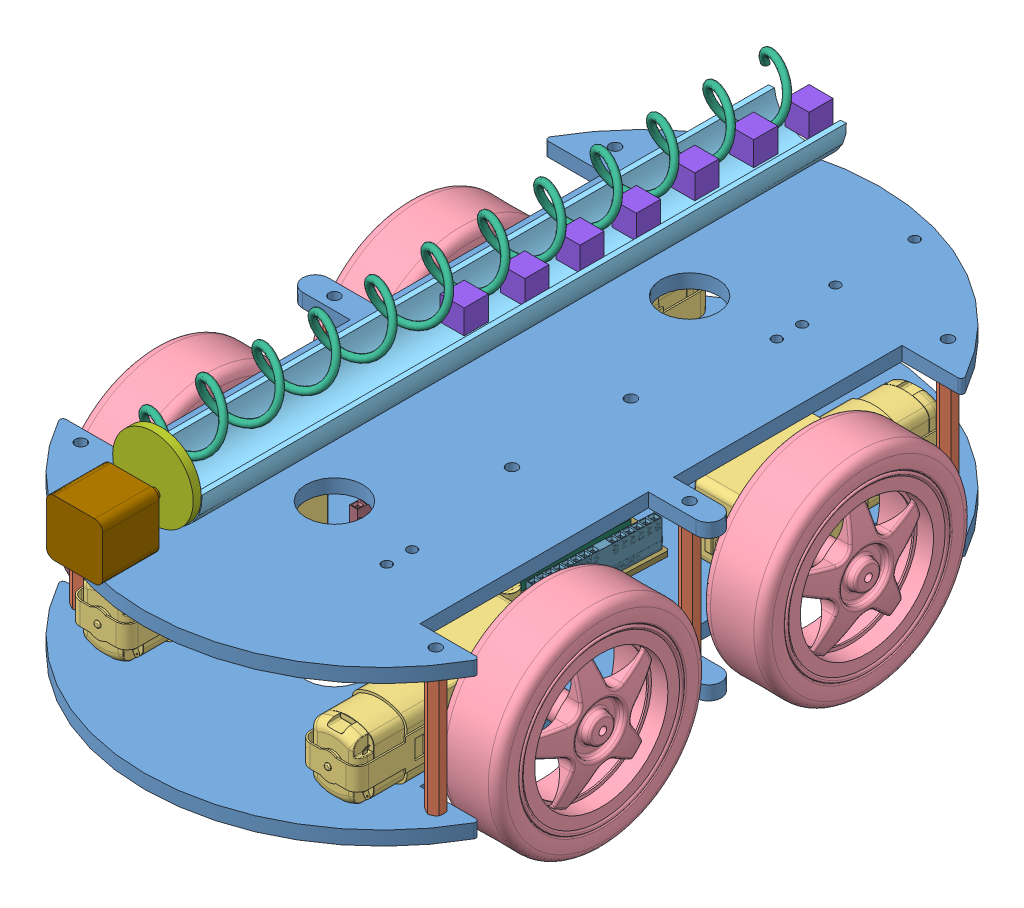
SolidWorks assembly mechatronics project assembly, configuration Default. Lengths in mm.
Overall size (144 110.42 232.39).
47 component instances, 28 part files, 49 mates.
Components (placement in the parent):
- Base Plate-1: Base Plate [Default] at origin size (132 4.4 231.81)
- Long Hex Nut-1: Long Hex Nut [B18.2.4.1M - Hex nut, Style 1,  M3 x 0.5 --D-N] at (-56 44.4 80) x (-0.471141 0 -0.882058) z (0 1 0) size (4.5 5.2 40)
- Long Hex Nut-5: Long Hex Nut [B18.2.4.1M - Hex nut, Style 1,  M3 x 0.5 --D-N] at (56 44.4 0) x (1 0 0) z (0 1 0) size (4.5 5.2 40)
- Long Hex Nut-6: Long Hex Nut [B18.2.4.1M - Hex nut, Style 1,  M3 x 0.5 --D-N] at (56 44.4 80) x (1 0 0) z (0 1 0) size (4.5 5.2 40)
- Long Hex Nut-7: Long Hex Nut [B18.2.4.1M - Hex nut, Style 1,  M3 x 0.5 --D-N] at (52.5 44.4 -85) x (1 0 0) z (0 1 0) size (4.5 5.2 40)
- Long Hex Nut-8: Long Hex Nut [B18.2.4.1M - Hex nut, Style 1,  M3 x 0.5 --D-N] at (-52.5 44.4 -85) x (1 0 0) z (0 1 0) size (4.5 5.2 40)
- Long Hex Nut-9: Long Hex Nut [B18.2.4.1M - Hex nut, Style 1,  M3 x 0.5 --D-N] at (-56 44.4 0) x (1 0 0) z (0 1 0) size (4.5 5.2 40)
- Base Plate-2: Base Plate [Default] at (0 44.4 0) size (132 4.4 231.81)
- Motor-1: Motor [Predeterminado] at (37.6 15.65 -77.2352) x (0 0 1) z (-1 0 0) size (69.7 22.5 36.8)
- Motor-2: Motor [Predeterminado] at (37.6 15.65 80.1311) x (0 0 -1) z (1 0 0) size (69.7 22.5 36.8)
- Motor-3: Motor [Predeterminado] at (-37.6 15.65 77.5479) x (0 0 -1) z (1 0 0) size (69.7 22.5 36.8)
- Motor-4: Motor [Predeterminado] at (-37.6 15.65 -76) x (0 0 1) z (-1 0 0) size (69.7 22.5 36.8)
- Wheel-1: Wheel [Predeterminado] at (-52 15.65 -39.2) x (-1 0 0) z (0 -0.685524 -0.72805) size (25 66 66)
- Wheel-2: Wheel [Predeterminado] at (52 15.65 -40.4352) x (1 0 0) z (0 0.941369 0.337378) size (25 66 66)
- Wheel-3: Wheel [Predeterminado] at (-52 15.65 40.7479) x (-1 0 0) z (0 -0.719414 -0.694582) size (25 66 66)
- Wheel-4: Wheel [Predeterminado] at (52 15.65 43.3311) x (1 0 0) z (0 -0.162012 0.986789) size (25 66 66)
- Part1-1: Part1 [Default] at (-21.5476 61.119 -114.7007) x (0.997351 0.072745 0) z (0 0 1) size (24.64 12.32 203.2)
- helical spring-1: helical spring [Default] at (-26.075 66.7384 -113.6168) size (19.58 19.58 205.37)
- disc-1: disc [Default] at (-22.1907 61.5 88.4993) x (0.653816 -0.756654 0) z (0 0 1) size (25.4 25.4 2.54)
- cube-1: cube [Default] at (-18.7394 62.6066 -98.7614) x (0.999993 0.003627 0) z (0 0.000021 1) size (7.62 7.62 7.62)
- cube-2: cube [Default] at (-19.6517 61.947 -81.1116) size (7.62 7.62 7.62)
- cube-3: cube [Default] at (-19.7614 60.024 -62.7963) size (7.62 7.62 7.62)
- cube-4: cube [Default] at (-19.8698 60.0971 -45.1118) size (7.62 7.62 7.62)
- cube-5: cube [Default] at (-20.004 59.5149 -27.8581) size (7.62 7.62 7.62)
- cube-6: cube [Default] at (-20.4205 60.6551 -9.1402) size (7.62 7.62 7.62)
- cube-7: cube [Default] at (-18.4626 61.6622 -115.9546) size (7.62 7.62 7.62)
- stepper motor-1: stepper motor [Default] at (-21.5488 57.69 98.6593) size (17.78 17.78 25.4)
- Ardi_UNO.STEP-1: Ardi_UNO.STEP [Default] at (-32.6159 2.8 38.091) x (0.039139 0 -0.999234) z (0 1 0) size (76.36 53.4 14.04)
  - Pins_3fach_q_001.STEP-1: Pins_3fach_q_001.STEP [Default] at (64.19 -23.29 3.21) size (5.08 7.62 11.94)
  - Pins_3fach_q_002.STEP-1: Pins_3fach_q_002.STEP [Default] at (15.78 -9.32 3.21) x (0 1 0) z (0 0 1) size (5.08 7.62 11.94)
  - Ardi_UNO_Platine_001.STEP-1: Ardi_UNO_Platine_001.STEP [Default] at origin size (69 53.4 1.61)
  - Headers_digital_001.STEP-1: Headers_digital_001.STEP [Default] at origin size (47.8 2.55 10.95)
  - Headers_Analog_001.STEP-1: Headers_Analog_001.STEP [Default] at origin size (38.85 2.55 10.95)
  - atmega328_socket_001.STEP-1: atmega328_socket_001.STEP [Default] at origin size (35.5 10 6.2)
  - atmega328_001.STEP-1: atmega328_001.STEP [Default] at origin size (35.36 8.18 5.99)
  - resetButton UNO_001.STEP-1: resetButton UNO_001.STEP [Default] at origin size (8.5 6.5 3.8)
  - USB_typeB_001.STEP-1: USB_typeB_001.STEP [Default] at (8.29 -16.56 3.2) x (0 -1 0) z (0 0 1) size (12.06 16.98 13.98)
  - Stromanschluss_arduino UNO_001.STEP-1: Stromanschluss_arduino UNO_001.STEP [Default] at origin size (14.2 9.2 13)
  - Kondensator_A8-47-25V_001.STEP-1: Kondensator_A8-47-25V_001.STEP [Default] at (-0.25 0 0) size (6.5 7.5 5)
  - Kondensator_A8-47-25V_002.STEP-1: Kondensator_A8-47-25V_002.STEP [Default] at (6.5 0 0) size (6.5 7.5 5)
  - Quarz_Arduino_16_001.STEP-1: Quarz_Arduino_16_001.STEP [Default] at origin size (12.5 4.5 5.2)
  - Transistor Arduino UNO_001.STEP-1: Transistor Arduino UNO_001.STEP [Default] at origin size (6.8 6.5 1.6)
  - LED Arduino UNO gelb_001.STEP-1: LED Arduino UNO gelb_001.STEP [Default] at origin size (2 1 0.5)
  - LED Arduino UNO gelb_002.STEP-1: LED Arduino UNO gelb_002.STEP [Default] at (0 -6 0) size (2 1 0.5)
  - LED Arduino UNO gelb_003.STEP-1: LED Arduino UNO gelb_003.STEP [Default] at (0 -8 0) size (2 1 0.5)
  - LED Arduino UNO gr__n_001.STEP-1: LED Arduino UNO gr__n_001.STEP [Default] at (30.5 -6 0) size (2 1 0.5)
  - achterTeil_001.STEP-1: achterTeil_001.STEP [Default] at origin size (3.2 4.7 0.8)
Mates (geometry in assembly coordinates):
- Coincident11: coincident anti-aligned: plane of Base Plate-1 through (0 4.4 0) normal (0 1 0); plane of Long Hex Nut-1 through (-53.8799 4.4 83.9693) normal (0 -1 0)
- Concentric1: concentric anti-aligned: circle of Base Plate-1; circle of Long Hex Nut-1
- Concentric21: concentric anti-aligned: cylinder of Base Plate-1 through (-18.75 0 18.75) axis (0 -1 0) radius 1.75; cylinder of Long Hex Nut-2 through (-18.75 19.3625 18.75) axis (0 1 0) radius 1.5
- Coincident21: coincident anti-aligned: plane of Base Plate-1 through (0 4.4 0) normal (0 1 0); plane of Long Hex Nut-2 through (-23.25 4.4 18.75) normal (0 -1 0)
- Coincident31: coincident anti-aligned: plane of Base Plate-1 through (0 4.4 0) normal (0 1 0); plane of Long Hex Nut-3 through (-27.4259 4.4 -36.2608) normal (0 -1 0)
- Concentric31: concentric anti-aligned: cylinder of Base Plate-1 through (20 0 -82) axis (0 -1 0) radius 1.5; cylinder of Long Hex Nut-4 through (20 19.3625 -82) axis (0 1 0) radius 1.5
- Coincident41: coincident anti-aligned: plane of Base Plate-1 through (0 4.4 0) normal (0 1 0); plane of Long Hex Nut-4 through (15.5 4.4 -82) normal (0 -1 0)
- Concentric41: concentric anti-aligned: cylinder of Base Plate-1 through (56 0 0) axis (0 -1 0) radius 1.75; cylinder of Long Hex Nut-5 through (56 19.3625 0) axis (0 1 0) radius 1.5
- Coincident51: coincident anti-aligned: plane of Base Plate-1 through (0 4.4 0) normal (0 1 0); plane of Long Hex Nut-5 through (51.5 4.4 0) normal (0 -1 0)
- Concentric51: concentric anti-aligned: cylinder of Base Plate-1 through (56 0 80) axis (0 -1 0) radius 1.75; cylinder of Long Hex Nut-6 through (56 19.3625 80) axis (0 1 0) radius 1.5
- Coincident61: coincident anti-aligned: plane of Base Plate-1 through (0 4.4 0) normal (0 1 0); plane of Long Hex Nut-6 through (51.5 4.4 80) normal (0 -1 0)
- Concentric81: concentric anti-aligned: cylinder of Base Plate-1 through (52.5 0 -85) axis (0 -1 0) radius 1.75; cylinder of Long Hex Nut-7 through (52.5 19.3625 -85) axis (0 1 0) radius 1.5
- Coincident71: coincident anti-aligned: plane of Base Plate-1 through (0 4.4 0) normal (0 1 0); plane of Long Hex Nut-7 through (48 4.4 -85) normal (0 -1 0)
- Concentric91: concentric anti-aligned: cylinder of Base Plate-1 through (-52.5 0 -85) axis (0 -1 0) radius 1.75; cylinder of Long Hex Nut-8 through (-52.5 19.3625 -85) axis (0 1 0) radius 1.5
- Coincident81: coincident anti-aligned: plane of Base Plate-1 through (0 4.4 0) normal (0 1 0); plane of Long Hex Nut-8 through (-57 4.4 -85) normal (0 -1 0)
- Concentric101: concentric anti-aligned: cylinder of Base Plate-1 through (-56 0 0) axis (0 -1 0) radius 1.75; cylinder of Long Hex Nut-9 through (-56 19.3625 0) axis (0 1 0) radius 1.5
- Coincident91: coincident anti-aligned: plane of Base Plate-1 through (0 4.4 0) normal (0 1 0); plane of Long Hex Nut-9 through (-60.5 4.4 0) normal (0 -1 0)
- Concentric11: concentric anti-aligned: circle of Long Hex Nut-1; cylinder of Base Plate-2 through (-56 44.4 80) axis (0 -1 0) radius 1.75
- Concentric12: concentric aligned: circle of Long Hex Nut-7; cylinder of Base Plate-2 through (52.5 44.4 -85) axis (0 -1 0) radius 1.75
- Coincident10: coincident anti-aligned: plane of Long Hex Nut-7 through (48 44.4 -85) normal (0 1 0); plane of Base Plate-2 through (0 44.4 0) normal (0 -1 0)
- Coincident11: coincident anti-aligned: plane of Base Plate-1 through (0 4.4 0) normal (0 1 0); plane of Motor-1 through (28.2 4.4 -31.5352) normal (0 -1 0)
- Coincident12: coincident aligned: plane of Base Plate-1 through (47 4.4 -76) normal (1 0 0); plane of Motor-1 through (47 6.7 -31.5352) normal (1 0 0)
- Coincident13: coincident anti-aligned: plane of Base Plate-1 through (0 4.4 0) normal (0 1 0); plane of Motor-4 through (-47 4.4 -30.3) normal (0 -1 0)
- Coincident14: coincident aligned: plane of Base Plate-1 through (-47 4.4 -76) normal (-1 0 0); plane of Motor-4 through (-47 6.7 -30.3) normal (-1 0 0)
- Coincident15: coincident anti-aligned: plane of Base Plate-1 through (0 4.4 0) normal (0 1 0); plane of Motor-3 through (-28.2 4.4 31.8479) normal (0 -1 0)
- Coincident16: coincident aligned: plane of Base Plate-1 through (-47 4.4 76) normal (-1 0 0); plane of Motor-3 through (-47 6.7 31.8479) normal (-1 0 0)
- Coincident17: coincident anti-aligned: plane of Base Plate-1 through (0 4.4 0) normal (0 1 0); plane of Motor-2 through (47 4.4 34.4311) normal (0 -1 0)
- Coincident18: coincident aligned: plane of Base Plate-1 through (47 4.4 76) normal (1 0 0); plane of Motor-2 through (47 6.7 34.4311) normal (1 0 0)
- Concentric13: concentric aligned: circle of Motor-2; circle of Wheel-4
- Coincident24: coincident aligned: circle of Motor-1; plane of Wheel-2 through (47 15.65 -40.4352) normal (-1 0 0)
- Parallel1: parallel anti-aligned: plane of Motor-1 through (56 15.65 -77.2352) normal (1 0 0); plane of Wheel-2 through (47 15.65 -40.4352) normal (-1 0 0)
- Coincident26: coincident anti-aligned: plane of Motor-2 through (47 6.7 34.4311) normal (1 0 0); plane of Wheel-4 through (47 15.65 43.3311) normal (-1 0 0)
- Coincident29: coincident anti-aligned: plane of Motor-1 through (47 6.7 -31.5352) normal (1 0 0); plane of Wheel-2 through (47 15.65 -40.4352) normal (-1 0 0)
- Concentric14: concentric anti-aligned: circle of Motor-1; circle of Wheel-2
- Concentric15: concentric aligned: circle of Motor-4; circle of Wheel-1
- Coincident30: coincident anti-aligned: plane of Motor-4 through (-47 6.7 -30.3) normal (-1 0 0); plane of Wheel-1 through (-47 15.65 -39.2) normal (1 0 0)
- Concentric16: concentric anti-aligned: circle of Motor-3; circle of Wheel-3
- Coincident31: coincident anti-aligned: plane of Motor-3 through (-47 6.7 31.8479) normal (-1 0 0); plane of Wheel-3 through (-47 15.65 40.7479) normal (1 0 0)
- Coincident35: coincident aligned: line of Base Plate-1 through (-47 4.4 -76) axis (0 -1 0); line of Motor-4 through (-47 21.9222 -76) axis (0 -1 0)
- Parallel4: parallel anti-aligned: line of Base Plate-1 through (47 4.4 -76) axis (0 -1 0); line of Motor-1 through (45.5 9.3778 -77.2352) axis (0 1 0)
- Tangent1: tangent anti-aligned: plane of Base Plate-2 through (0 48.8 0) normal (0 1 0); cylinder of Part1-1 through (-21.5476 61.119 88.4993) axis (0 0 -1) radius 12.319
- Coincident93: coincident anti-aligned: plane of Part1-1 through (-21.5476 61.119 88.4993) normal (0 0 1); plane of disc-1 through (-22.1907 61.5 88.4993) normal (0 0 -1)
- Tangent3: tangent anti-aligned: plane of Base Plate-2 through (0 48.8 0) normal (0 1 0); cylinder of disc-1 through (-22.1907 61.5 91.0393) axis (0 0 -1) radius 12.7
- Parallel5: parallel aligned: cylinder of Part1-1 through (-21.5476 61.119 88.4993) axis (0 0 -1) radius 12.319; cylinder of disc-1 through (-22.1907 61.5 91.0393) axis (0 0 -1) radius 12.7
- Tangent5: tangent: circle of helical spring-1; plane of disc-1 through (-22.1907 61.5 88.4993) normal (0 0 -1)
- Coincident94: coincident anti-aligned: plane of Base Plate-2 through (0 48.8 0) normal (0 1 0); plane of stepper motor-1 through (-30.4388 48.8 116.4393) normal (0 -1 0)
- Coincident95: coincident anti-aligned: plane of disc-1 through (-22.1907 61.5 91.0393) normal (0 0 1); plane of stepper motor-1 through (-21.5488 57.69 91.0393) normal (0 0 -1)
- Coincident96: coincident anti-aligned: plane of Base Plate-1 through (0 4.4 0) normal (0 1 0); plane of Ardi_UNO.STEP-1/Ardi_UNO_Platine_001.STEP-1 through (-4.4777 4.4 5.4847) normal (0 -1 0)
- Coincident97: coincident: cylinder of Motor-4 through (-28.7 24.6 -28.5) axis (0 -1 0) radius 0.5; line of Ardi_UNO.STEP-1/Ardi_UNO_Platine_001.STEP-1 through (-28.2467 4.4 -28.2889) axis (0 1 0)
